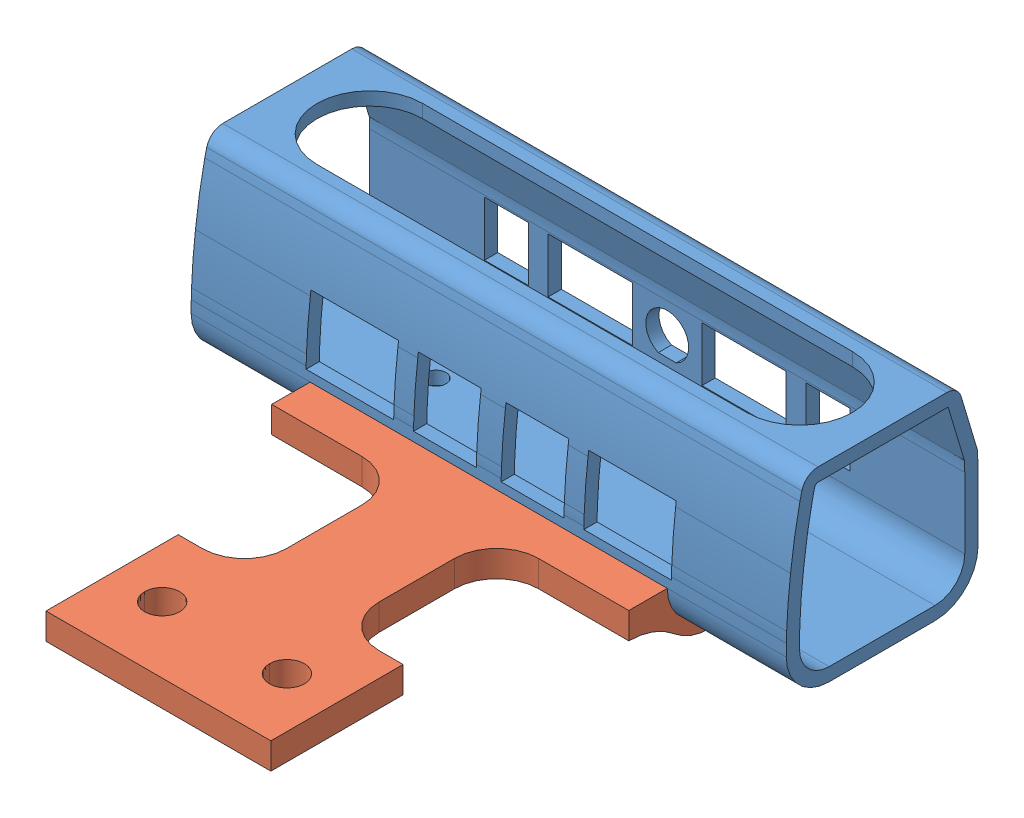
SolidWorks assembly Assem_Camera[1], configuration Default. Lengths in mm.
Overall size (90 31.02 78.97).
2 component instances, 2 part files, 3 mates.
Components (placement in the parent):
- Camera Cabinet_R1.catpart-1: Camera Cabinet_R1.catpart [Default] at (-22.2711 43.8941 71.473) size (90 29.02 29.03)
- Camera Fixture.catpart-1: Camera Fixture.catpart [Default] at (-4.2755 43.9179 71.4304) size (54.01 8.5 72.5)
Mates (geometry in assembly coordinates):
- Coincident3: coincident anti-aligned: plane of Camera Cabinet_R1.catpart-1 through (-22.2711 37.3941 79.473) normal (0 -1 0); plane of Camera Fixture.catpart-1 through (-4.2755 37.3941 63.4178) normal (0 1 0)
- Concentric1: concentric aligned: cylinder of Camera Cabinet_R1.catpart-1 through (0.2289 37.3941 71.4241) axis (0 -1 0) radius 1.5; cylinder of Camera Fixture.catpart-1 through (0.2289 35.3941 71.4241) axis (0 -1 0) radius 1.5
- Concentric2: concentric aligned: cylinder of Camera Cabinet_R1.catpart-1 through (45.2289 37.3941 71.4241) axis (0 -1 0) radius 1.5; cylinder of Camera Fixture.catpart-1 through (45.2289 35.3941 71.4241) axis (0 -1 0) radius 1.5
